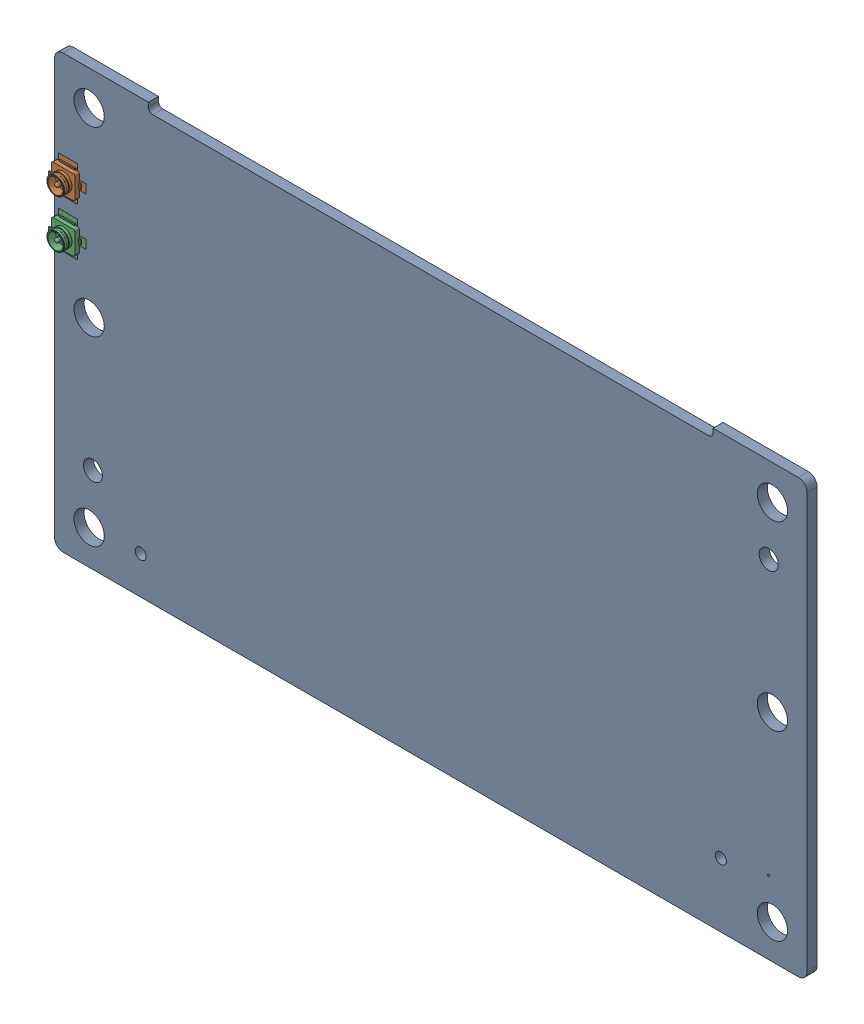
SolidWorks assembly 244-83310-1000-C03_ASM, configuration Default. Lengths in mm.
Overall size (87 50 7.77).
4 component instances, 3 part files, 0 mates.
Components (placement in the parent):
- 142-83310-1000-C03-1: 142-83310-1000-C03 [Default] at origin size (87 50 1.16)
- 080-0550-000_2-1: 080-0550-000_2 [Default] at (-2.36 33.789 1.164) size (3.63 4.07 1.47)
- 080-0550-000_2-2: 080-0550-000_2 [Default] at (-2.36 28.232 1.164) size (3.63 4.07 1.47)
- 080-1337-000_1-1: 080-1337-000_1 [Default] at (39.5 3.4 0) x (1 0 0) z (0 0 -1) size (70.16 10.74 5.05)
